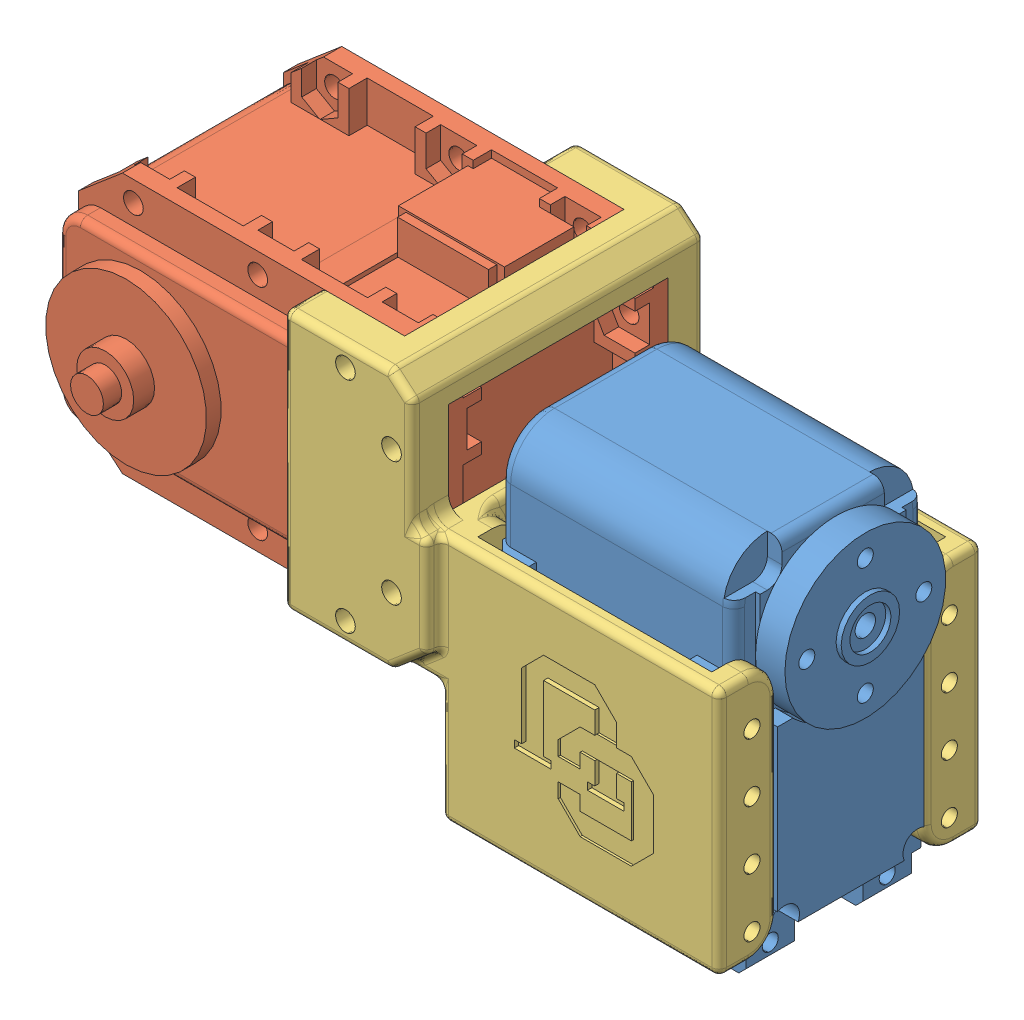
SolidWorks assembly wrist_pitch_link, configuration Default. Lengths in mm.
Overall size (201.45 138.54 118.82).
3 component instances, 3 part files, 8 mates.
Components (placement in the parent):
- AX-12-1: AX-12 [Default] at (59.6 0 0) x (0 0 -1) z (1 0 0) size (32 50 40.7)
- RX-28-1: RX-28 [Default] x (0 1 0) z (0 0 1) size (117.84 201.45 118.07)
- Custom Frame - RX-28 to AX-12 for Old Gripper-1: Custom Frame - RX-28 to AX-12 for Old Gripper [Default] at (29.8 0 15) x (1 0 0) z (0 -1 0) size (57.6 40 51.8)
Mates (geometry in assembly coordinates):
- Coincident122: coincident anti-aligned: plane of AX-12-1 through (74.6864 -34.412 16) normal (0 0 1); plane of Custom Frame - RX-28 to AX-12 for Old Gripper-1 through (40.6 0 16) normal (0 0 -1)
- Concentric75: concentric anti-aligned: cylinder of AX-12-1 through (75.72 -6.5 13.5) axis (-1 0 0) radius 1.1; cylinder of Custom Frame - RX-28 to AX-12 for Old Gripper-1 through (20.999 -6.5 13.5) axis (1 0 0) radius 1.1
- Coincident123: coincident anti-aligned: plane of AX-12-1 through (75.6 -38.38 15.6) normal (1 0 0); plane of Custom Frame - RX-28 to AX-12 for Old Gripper-1 through (75.6 0 10) normal (-1 0 0)
- Coincident120: coincident anti-aligned: plane of RX-28-1 through (-12 -17.8 -17.75) normal (0 0 -1); plane of Custom Frame - RX-28 to AX-12 for Old Gripper-1 through (33 12.2 -17.75) normal (0 0 1)
- Concentric73: concentric anti-aligned: cylinder of RX-28-1 through (35.8 8.5 -12.5) axis (0 0 1) radius 1.35; cylinder of Custom Frame - RX-28 to AX-12 for Old Gripper-1 through (35.8 8.5 -15) axis (0 0 -1) radius 1.35
- Concentric74: concentric aligned: cylinder of RX-28-1 through (29.5 -15 -15) axis (0 0 -1) radius 1.35; cylinder of Custom Frame - RX-28 to AX-12 for Old Gripper-1 through (29.5 -15 -15) axis (0 0 -1) radius 1.35
- Coincident126: coincident aligned: plane of RX-28-1; plane of assembly through (0 0 0) normal (1 0 0)
- Coincident127: coincident aligned: plane of RX-28-1 through (0 0 0) normal (0 0 1); plane of assembly through (0 0 0) normal (0 0 1)
